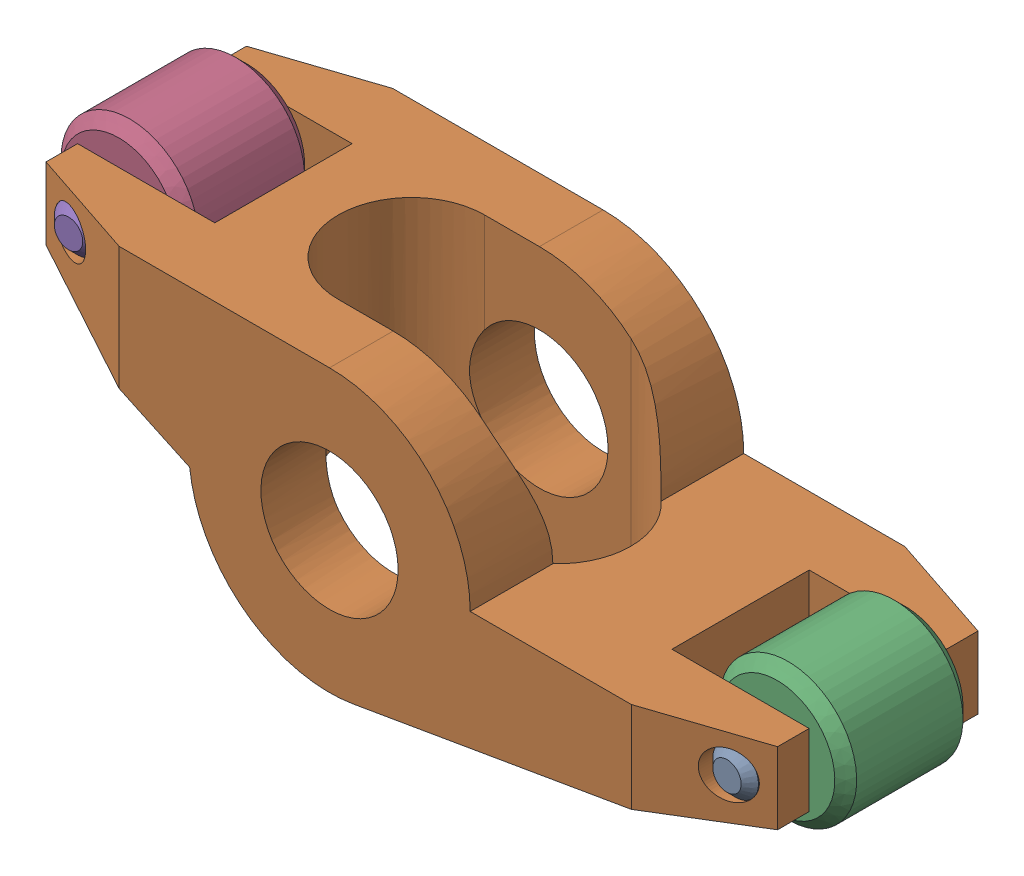
SolidWorks assembly rockerArm_assembly, configuration Default. Lengths in mm.
Overall size (57.7 23.35 19).
5 component instances, 3 part files, 8 mates.
Components (placement in the parent):
- pin2_rockerArm-1: pin2_rockerArm [Default] at (-7.2827 8.7883 22.3969) x (0.705407 0.708802 0) z (0 0 1) size (3.17 3.17 15.87)
- rocker_head-1: rocker_head [Default] at (-33.3227 11.3283 22.3969) size (50.81 19.54 19)
- wheel_RockerArm-1: wheel_RockerArm [Default] at (-7.2827 8.7883 22.3969) x (0.97977 -0.200125 0) z (0 0 1) size (9.53 9.53 8.9)
- wheel_RockerArm-3: wheel_RockerArm [Default] at (-53.0127 18.5583 22.3969) x (0.902796 0.430069 0) z (0 0 1) size (9.53 9.53 8.9)
- pin2_rockerArm-2: pin2_rockerArm [Default] at (-53.0127 18.5583 22.3969) x (0.584102 0.81168 0) z (0 0 1) size (3.17 3.17 15.87)
Mates (geometry in assembly coordinates):
- Concentric2: concentric anti-aligned: cylinder of rocker_head-1 through (-7.2827 8.7883 31.8969) axis (0 0 -1) radius 1.59; cylinder of wheel_RockerArm-1 through (-7.2827 8.7883 34.8975) axis (0 0 1) radius 1.59
- Width2: width aligned: plane of wheel_RockerArm-1 through (-6.4812 12.7123 26.8469) normal (0 0 1); plane of rocker_head-1 through (-6.9646 10.3462 17.9469) normal (0 0 -1); plane of wheel_RockerArm-1 through (-33.3227 11.3283 31.8969) normal (0 0 1); plane of rocker_head-1 through (-33.3227 11.3283 12.8969) normal (0 0 -1)
- Concentric3: concentric aligned: cylinder of pin2_rockerArm-1 through (-7.2827 8.7883 30.3319) axis (0 0 -1) radius 1.585; cylinder of rocker_head-1 through (-7.2827 8.7883 31.8969) axis (0 0 -1) radius 1.59
- Width3: width aligned: plane of pin2_rockerArm-1 through (-7.2827 8.7883 30.3319) normal (0 0 1); plane of rocker_head-1 through (-7.2827 8.7883 14.4619) normal (0 0 -1); plane of pin2_rockerArm-1 through (-33.3227 11.3283 31.8969) normal (0 0 1); plane of rocker_head-1 through (-33.3227 11.3283 12.8969) normal (0 0 -1)
- Concentric5: concentric anti-aligned: cylinder of rocker_head-1 through (-53.0127 18.5583 31.8969) axis (0 0 -1) radius 1.59; cylinder of wheel_RockerArm-3 through (-53.0127 18.5583 34.8975) axis (0 0 1) radius 1.59
- Width5: width aligned: plane of wheel_RockerArm-3 through (-54.7352 22.174 26.8469) normal (0 0 1); plane of rocker_head-1 through (-53.6966 19.9938 17.9469) normal (0 0 -1); plane of wheel_RockerArm-3 through (-33.3227 11.3283 31.8969) normal (0 0 1); plane of rocker_head-1 through (-33.3227 11.3283 12.8969) normal (0 0 -1)
- Concentric6: concentric aligned: cylinder of rocker_head-1 through (-53.0127 18.5583 31.8969) axis (0 0 -1) radius 1.59; cylinder of pin2_rockerArm-2 through (-53.0127 18.5583 30.3319) axis (0 0 -1) radius 1.585
- Width7: width aligned: plane of pin2_rockerArm-2 through (-53.0127 18.5583 30.3319) normal (0 0 1); plane of rocker_head-1 through (-53.0127 18.5583 14.4619) normal (0 0 -1); plane of pin2_rockerArm-2 through (-33.3227 11.3283 31.8969) normal (0 0 1); plane of rocker_head-1 through (-33.3227 11.3283 12.8969) normal (0 0 -1)
